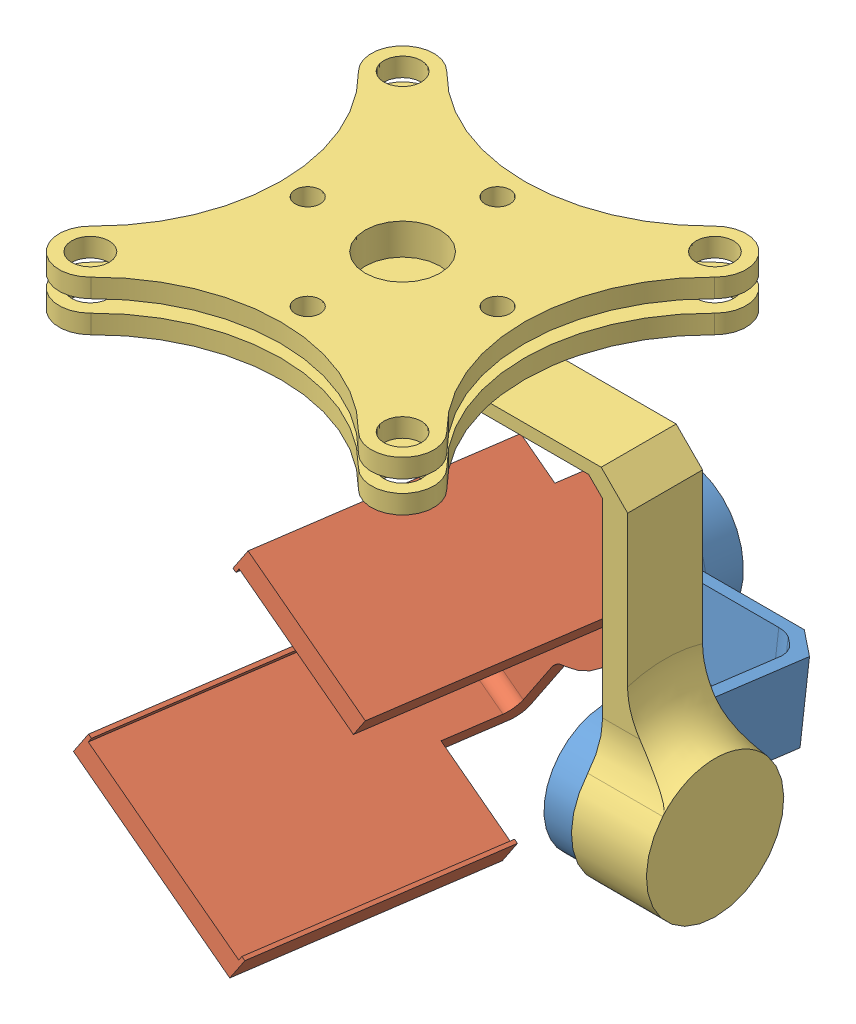
SolidWorks assembly Gimbal Assembly Modified, configuration Default. Lengths in mm.
Overall size (202.66 224.67 194.75).
3 component instances, 3 part files, 6 mates.
Components (placement in the parent):
- Pitch-2: Pitch [Default] at (52.6099 -67.3948 -98.4938) x (0 -0.126417 -0.991977) z (0 -0.991977 0.126417) size (134.55 134.07 55)
- Roll-2: Roll [Default] at (-28.9572 -75.7447 -164.0139) x (-0.528158 -0.842333 0.107347) z (0.849146 -0.523921 0.066768) size (110 165 80)
- Yaw-2: Yaw [Default] at (-28.9616 48.2367 -98.4938) size (202.66 168.13 150)
Mates (geometry in assembly coordinates):
- Parallel1: parallel anti-aligned: plane of Pitch-2 through (77.6099 -67.3948 -98.4938) normal (1 0 0); plane of Yaw-2 through (66.1099 -67.3948 -83.4938) normal (-1 0 0)
- Concentric1: concentric aligned: cylinder of Pitch-2 through (77.6099 -67.3948 -98.4938) axis (-1 0 0) radius 25; cylinder of Yaw-2 through (91.1099 -67.3948 -98.4938) axis (-1 0 0) radius 25.5
- Distance1: distance = 21 mm anti-aligned: plane of Yaw-2 through (91.1099 -67.3948 -98.4938) normal (-1 0 0); plane of Pitch-2 through (70.1099 -67.3948 -98.4938) normal (1 0 0)
- Parallel2: parallel anti-aligned: plane of Pitch-2 through (-28.9572 -92.331 -175.5093) normal (0 0.126417 0.991977); plane of Roll-2 through (-28.9572 -78.9051 -188.8133) normal (0 -0.126417 -0.991977)
- Concentric2: concentric aligned: cylinder of Pitch-2 through (-28.9572 -80.6118 -202.205) axis (0 0.126417 0.991977) radius 25.5; cylinder of Roll-2 through (-28.9572 -78.9051 -188.8133) axis (0 0.126417 0.991977) radius 25
- Distance2: distance = 21 mm anti-aligned: plane of Pitch-2 through (-28.9572 -80.6118 -202.205) normal (0 0.126417 0.991977); plane of Roll-2 through (-28.9572 -77.957 -181.3735) normal (0 -0.126417 -0.991977)
